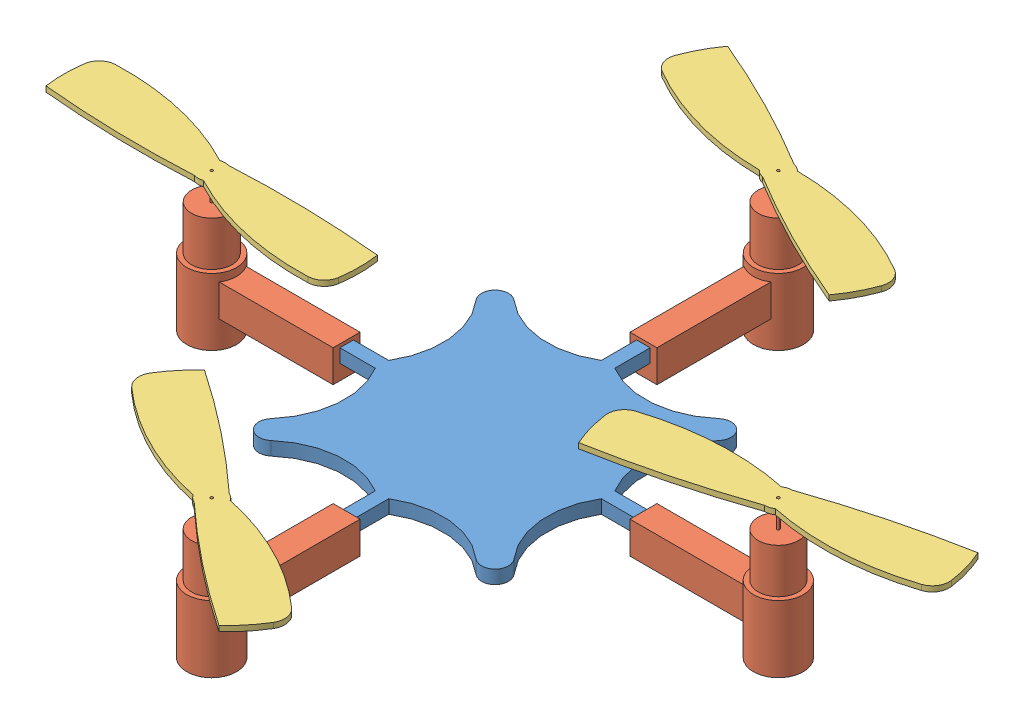
SolidWorks assembly crazyflie-assembly, configuration Default. Lengths in mm.
Overall size (131.75 20.5 112.79).
9 component instances, 3 part files, 21 mates.
Components (placement in the parent):
- crazyflie-1: crazyflie [Default] at (19.8905 -3.11 -8.3831) size (84 2 84)
- crazyflie-motor-1: crazyflie-motor [Default] at (-3.3786 -9.36 -48.1368) x (0.989017 0 -0.1478) z (0.1478 0 0.989017) size (8.63 20.5 23.78)
- crazyflie-motor-2: crazyflie-motor [Default] at (38.6214 -9.36 -6.1368) x (0.1478 0 0.989017) z (-0.989017 0 0.1478) size (8.63 20.5 23.78)
- crazyflie-motor-3: crazyflie-motor [Default] at (-45.3786 -9.36 -6.1368) x (-0.1478 0 -0.989017) z (0.989017 0 -0.1478) size (8.63 20.5 23.78)
- crazyflie-motor-4: crazyflie-motor [Default] at (-3.3786 -9.36 35.8632) x (-0.989017 0 0.1478) z (-0.1478 0 -0.989017) size (8.63 20.5 23.78)
- crazyflie-propeller-1: crazyflie-propeller [Default] at (-20.8704 11.14 19.5779) x (0.536816 0 -0.843699) z (-0.843699 0 -0.536816) size (8.7 0.8 47)
- crazyflie-propeller-2: crazyflie-propeller [Default] at (61.1786 10.34 -14.0329) x (-0.153077 0 -0.988214) z (0.988214 0 -0.153077) size (8.7 0.8 47)
- crazyflie-propeller-3: crazyflie-propeller [Default] at (16.987 11.14 -35.6302) x (-0.359463 0 0.93316) z (0.93316 0 0.359463) size (8.7 0.8 47)
- crazyflie-propeller-4: crazyflie-propeller [Default] at (-21.5196 10.34 -7.5222) x (0.124707 0 -0.992194) z (0.992194 0 0.124707) size (8.7 0.8 47)
Mates (geometry in assembly coordinates):
- Coincident1: coincident anti-aligned: plane of crazyflie-1 through (-4.3786 -1.11 -48.1368) normal (0 0 -1); plane of crazyflie-motor-1 through (-3.3786 -9.36 -48.1368) normal (0 0 1)
- Coincident2: coincident anti-aligned: plane of crazyflie-1 through (-19.8786 -1.11 -22.6368) normal (0 1 0); plane of crazyflie-motor-1 through (-5.3786 -1.11 -48.1368) normal (0 -1 0)
- Coincident3: coincident anti-aligned: plane of crazyflie-1 through (-4.3786 -1.11 -48.1368) normal (-1 0 0); plane of crazyflie-motor-1 through (-4.3786 -5.36 -48.1368) normal (1 0 0)
- Coincident15: coincident anti-aligned: plane of crazyflie-1 through (38.6214 -1.11 -7.1368) normal (1 0 0); plane of crazyflie-motor-2 through (38.6214 -9.36 -6.1368) normal (-1 0 0)
- Coincident16: coincident anti-aligned: plane of crazyflie-1 through (38.6214 -1.11 -7.1368) normal (0 0 -1); plane of crazyflie-motor-2 through (38.6214 -5.36 -7.1368) normal (0 0 1)
- Coincident17: coincident anti-aligned: plane of crazyflie-1 through (-19.8786 -1.11 -22.6368) normal (0 1 0); plane of crazyflie-motor-2 through (38.6214 -1.11 -8.1368) normal (0 -1 0)
- Coincident18: coincident anti-aligned: plane of crazyflie-1 through (-45.3786 -1.11 -7.1368) normal (-1 0 0); plane of crazyflie-motor-3 through (-45.3786 -9.36 -6.1368) normal (1 0 0)
- Coincident19: coincident anti-aligned: plane of crazyflie-1 through (-45.3786 -1.11 -7.1368) normal (0 0 -1); plane of crazyflie-motor-3 through (-45.3786 -5.36 -7.1368) normal (0 0 1)
- Coincident20: coincident anti-aligned: plane of crazyflie-1 through (-19.8786 -1.11 -22.6368) normal (0 1 0); plane of crazyflie-motor-3 through (-45.3786 -1.11 -4.1368) normal (0 -1 0)
- Coincident21: coincident anti-aligned: plane of crazyflie-1 through (-4.3786 -1.11 35.8632) normal (0 0 1); plane of crazyflie-motor-4 through (-3.3786 -9.36 35.8632) normal (0 0 -1)
- Coincident22: coincident anti-aligned: plane of crazyflie-1 through (-19.8786 -1.11 -22.6368) normal (0 1 0); plane of crazyflie-motor-4 through (-1.3786 -1.11 35.8632) normal (0 -1 0)
- Coincident23: coincident anti-aligned: plane of crazyflie-1 through (-4.3786 -1.11 35.8632) normal (-1 0 0); plane of crazyflie-motor-4 through (-4.3786 -5.36 35.8632) normal (1 0 0)
- Coincident24: coincident aligned: plane of crazyflie-motor-3 through (-45.3786 11.14 -6.1368) normal (0 1 0); plane of crazyflie-propeller-4 through (-57.3834 11.14 -8.8387) normal (0 1 0)
- Concentric1: concentric aligned: cylinder of crazyflie-motor-3 through (-45.3786 11.14 -6.1368) axis (0 -1 0) radius 0.2; cylinder of crazyflie-propeller-4 through (-45.3786 11.14 -6.1368) axis (0 -1 0) radius 0.2
- Coincident26: coincident aligned: plane of crazyflie-motor-2 through (38.6214 11.14 -6.1368) normal (0 1 0); plane of crazyflie-propeller-2 through (26.3365 11.14 -5.4317) normal (0 1 0)
- Coincident27: coincident aligned: plane of crazyflie-motor-2 through (38.6214 11.14 -6.1368) normal (0 1 0); plane of crazyflie-propeller-2 through (26.3365 11.14 -5.4317) normal (0 1 0)
- Concentric3: concentric aligned: cylinder of crazyflie-motor-2 through (38.6214 11.14 -6.1368) axis (0 -1 0) radius 0.2; cylinder of crazyflie-propeller-2 through (38.6214 11.14 -6.1368) axis (0 -1 0) radius 0.2
- Concentric5: concentric anti-aligned: cylinder of crazyflie-motor-1 through (-3.3786 11.14 -48.1368) axis (0 -1 0) radius 0.2; cylinder of crazyflie-propeller-3 through (-3.3786 10.34 -48.1368) axis (0 1 0) radius 0.2
- Coincident31: coincident aligned: plane of crazyflie-motor-1 through (-3.3786 11.14 -48.1368) normal (0 1 0); plane of crazyflie-propeller-3 through (-15.2335 11.14 -51.4349) normal (0 1 0)
- Concentric6: concentric anti-aligned: cylinder of crazyflie-motor-4 through (-3.3786 11.14 35.8632) axis (0 -1 0) radius 0.2; cylinder of crazyflie-propeller-1 through (-3.3786 10.34 35.8632) axis (0 1 0) radius 0.2
- Coincident32: coincident aligned: plane of crazyflie-motor-4 through (-3.3786 11.14 35.8632) normal (0 1 0); plane of crazyflie-propeller-1 through (7.5906 11.14 41.4394) normal (0 1 0)
